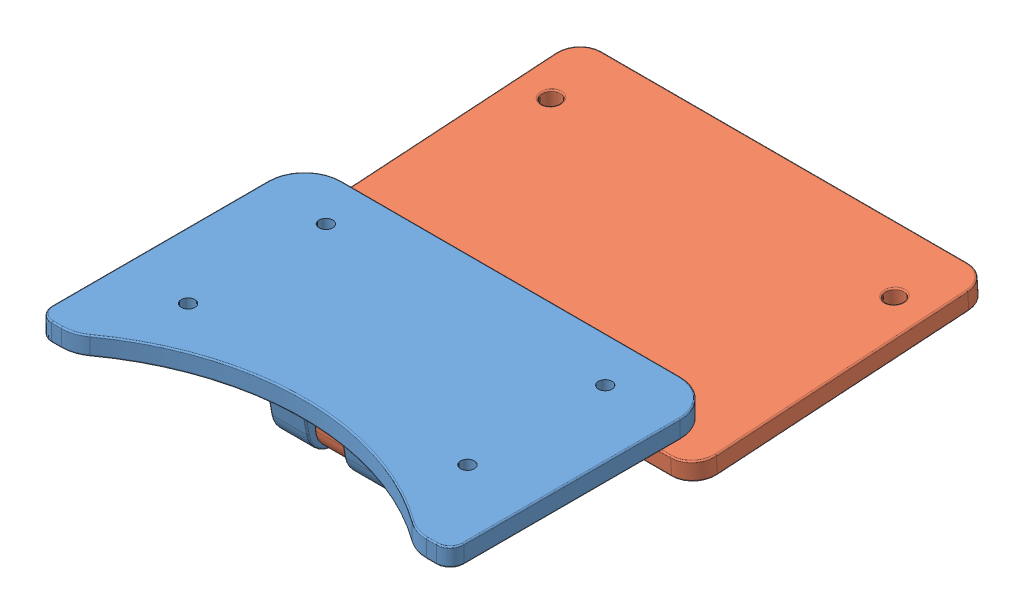
SolidWorks assembly 显示器支架装配, configuration 默认. Lengths in mm.
Overall size (90 24.66 118.75).
2 component instances, 2 part files, 2 mates.
Components (placement in the parent):
- 机器人显示器支架v2-1: 机器人显示器支架v2 [默认] at (-37.9685 -93.4546 -43.2224) size (90 24.5 58.24)
- 显示器支架B-1: 显示器支架B [默认] at (-37.9685 -98.6442 -68.624) x (-1 0 0) z (0 -0.065318 0.997864) size (90 11.57 96.71)
Mates (geometry in assembly coordinates):
- 重合2: coincident: plane of 机器人显示器支架v2-1 through (-25.9685 -122.4546 -6.7768) normal (-1 0 0); plane of 显示器支架B-1 through (-25.9685 -98.6442 -68.624) normal (1 0 0)
- 同心2: concentric aligned: cylinder of 机器人显示器支架v2-1 through (-77.9685 -108.0436 -20.2993) axis (1 0 0) radius 3; cylinder of 显示器支架B-1 through (-84.4685 -108.0436 -20.2993) axis (1 0 0) radius 3
